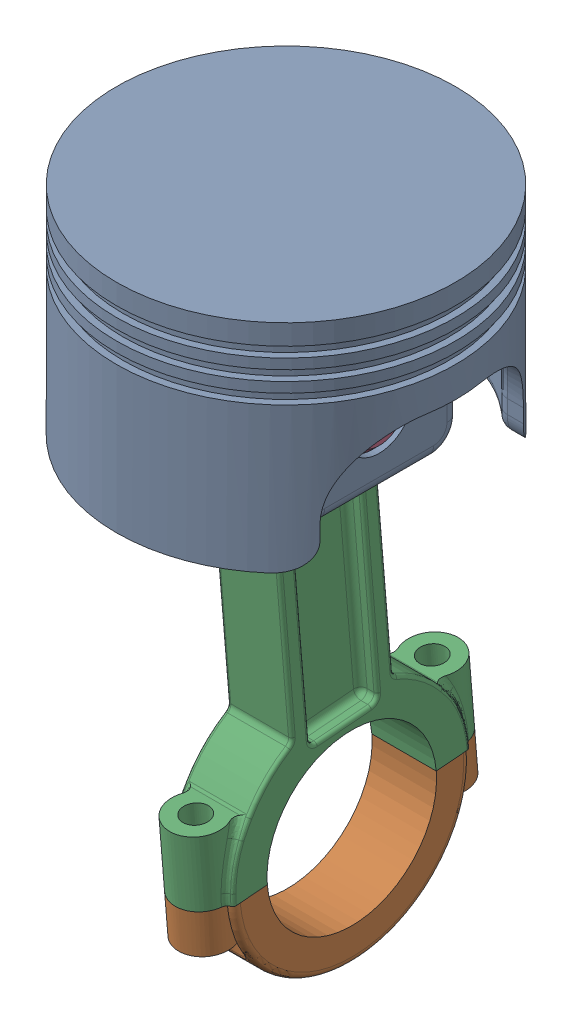
SolidWorks assembly Piston Assembly, configuration Default. Lengths in mm.
Overall size (127 257.75 133.75).
4 component instances, 4 part files, 7 mates.
Components (placement in the parent):
- Piston-1: Piston [Default] at (31.5939 80.1309 53.9213) size (127 82.5 127)
- Cap Rod Piston-1: Cap Rod Piston [Default] at (31.5989 -109.8502 41.355) x (0 0.082456 -0.996595) z (-1 0 0) size (108.4 44.45 24.13)
- Connecting Rod-1: Connecting Rod [Default] at (31.5989 42.0309 53.9213) x (0 -0.996595 -0.082456) z (-1 0 0) size (190.5 108.4 31.75)
- Piston Pin-1: Piston Pin [Default] at (-3.3761 42.0309 53.9213) x (0 0.027 -0.999635) z (1 0 0) size (25.4 25.4 69.85)
Mates (geometry in assembly coordinates):
- Concentric1: concentric aligned: cylinder of Piston-1 through (-31.9061 42.0309 53.9213) axis (1 0 0) radius 12.7; cylinder of Connecting Rod-1 through (19.5339 42.0309 53.9213) axis (1 0 0) radius 25.4
- Coincident1: coincident anti-aligned: plane of Piston-1 through (47.4739 16.6309 23.5213) normal (-1 0 0); plane of Connecting Rod-1 through (47.4739 42.0309 53.9213) normal (1 0 0)
- Concentric2: concentric anti-aligned: cylinder of Piston-1 through (-31.9061 42.0309 53.9213) axis (1 0 0) radius 12.7; cylinder of Piston Pin-1 through (66.4739 42.0309 53.9213) axis (-1 0 0) radius 12.7
- Coincident2: coincident aligned: plane of Piston-1 through (66.4739 16.6309 23.5213) normal (1 0 0); plane of Piston Pin-1 through (66.4739 42.0309 53.9213) normal (1 0 0)
- Coincident3: coincident anti-aligned: plane of Cap Rod Piston-1 through (19.5339 -113.5153 85.6536) normal (0 0.996595 0.082456); plane of Connecting Rod-1 through (19.5339 -109.8502 41.355) normal (0 -0.996595 -0.082456)
- Concentric3: concentric anti-aligned: circle of Cap Rod Piston-1; circle of Connecting Rod-1
- Concentric4: concentric aligned: circle of Cap Rod Piston-1; circle of Connecting Rod-1
